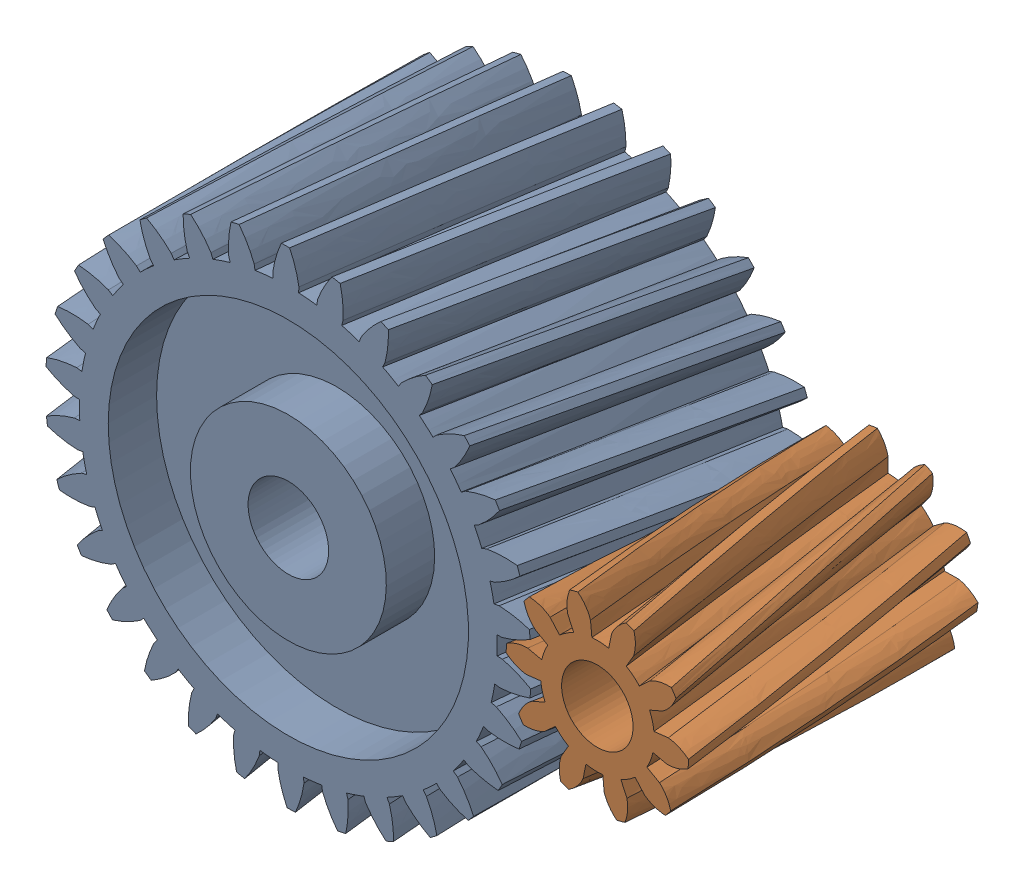
SolidWorks assembly Assem4, configuration Default. Lengths in mm.
Overall size (145.83 113.85 104.5).
2 component instances, 2 part files, 4 mates.
Components (placement in the parent):
- Gear 1-1: Gear 1 [Default] at (636.1037 0 1323.5171) x (0.990675 -0.13625 0) z (0 0 1) size (100.93 101.04 60.36)
- Gear 2-1: Gear 2 [Default] at (700.01 0 1323.5171) x (0.910073 0.414448 0) z (0 0 1) size (37.77 37.91 60)
Mates (geometry in assembly coordinates):
- Coincident1: coincident aligned: plane of Gear 1-1 through (643.4504 46.802 1323.5171) normal (0 0 1); plane of Gear 2-1 through (697.5605 16.7557 1323.5171) normal (0 0 1)
- Concentric6: concentric aligned: cylinder of Gear 1-1 through (636.1037 0 1263.1554) axis (0 0 1) radius 8.33
- Coincident4: coincident: plane of Gear 1-1 through (643.4504 46.802 1323.5171) normal (0 0 1)
- Concentric7: concentric aligned: cylinder of Gear 2-1 through (700.01 0 1263.5171) axis (0 0 1) radius 7.3933
